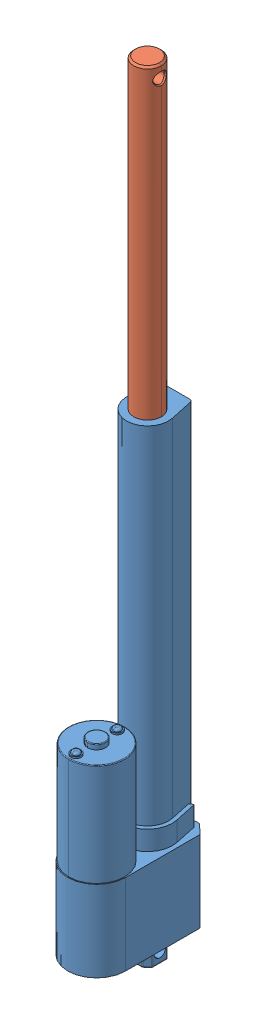
SolidWorks assembly HDA8 assembly, configuration Default. Lengths in mm.
Overall size (41.86 564.97 81.56).
2 component instances, 2 part files, 7 mates.
Components (placement in the parent):
- HDA8-1: HDA8 [Default] at origin size (41.86 343.57 81.56)
- HDA8 shaft-1: HDA8 shaft [Default] at (0 259.08 -36.8427) x (0 0 -1) z (1 0 0) size (19.96 285.92 19.97)
Mates (geometry in assembly coordinates):
- Coincident1: coincident aligned: plane of HDA8-1 through (0 0 0) normal (0 0 1)
- Coincident2: coincident aligned: plane of HDA8-1 through (0 0 0) normal (0 1 0)
- Coincident3: coincident aligned: plane of HDA8-1 through (0 0 0) normal (1 0 0)
- Concentric1: concentric anti-aligned: cylinder of HDA8-1 through (0 30.4401 -36.8427) axis (0 1 0) radius 9.9822; cylinder of HDA8 shaft-1 through (0 544.9951 -36.8427) axis (0 -1 0) radius 9.9822
- LimitDistance1: limit distance = 547.878 mm: point of HDA8-1; unknown of HDA8 shaft-1
- Parallel1: parallel anti-aligned: cylinder of HDA8-1 through (-8.89 -12.065 -36.8427) axis (-1 0 0) radius 4.1021; cylinder of HDA8 shaft-1 through (16.1574 535.813 -36.8427) axis (1 0 0) radius 4.1021
- Distance1: distance = 347.98 mm: cylinder of HDA8-1 through (-8.89 -12.065 -36.8427) axis (-1 0 0) radius 4.1021; cylinder of HDA8 shaft-1 through (16.1574 535.813 -36.8427) axis (1 0 0) radius 4.1021
